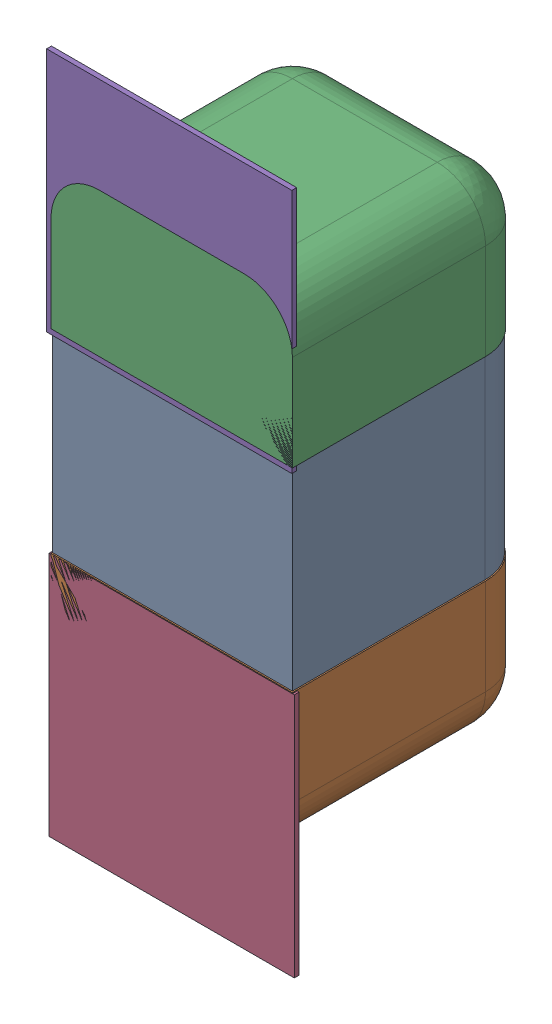
SolidWorks assembly C60, configuration Défaut. Lengths in mm.
Overall size (0.51 1.41 0.5).
8 component instances, 4 part files, 0 mates.
Components (placement in the parent):
- 6501210464-1: 6501210464 [Défaut] at (12.7762 -23.1068 -2.0818) x (0 1 0) z (-1 0 0) size (1 0.5 0.5)
  - Open CASCADE STEP translator 7.5 2.33.1.1-1: Open CASCADE STEP translator 7.5 2.33.1.1 [Défaut] at origin size (0.4 0.5 0.5)
  - Open CASCADE STEP translator 7.5 2.33.1.2-1: Open CASCADE STEP translator 7.5 2.33.1.2 [Défaut] at origin size (0.3 0.5 0.5)
  - Open CASCADE STEP translator 7.5 2.33.1.3-1: Open CASCADE STEP translator 7.5 2.33.1.3 [Défaut] at origin size (0.3 0.5 0.5)
- 6504207776-1: 6504207776 [Défaut] at (12.7762 -23.5641 -2.0918) size (0.51 0.51 0.01)
  - Extruded-1: Extruded [Défaut] at origin size (0.51 0.51 0.01)
- 6504207776-2: 6504207776 [Défaut] at (12.771 -22.6618 -2.0918) size (0.51 0.51 0.01)
  - Extruded-1: Extruded [Défaut] at origin size (0.51 0.51 0.01)
